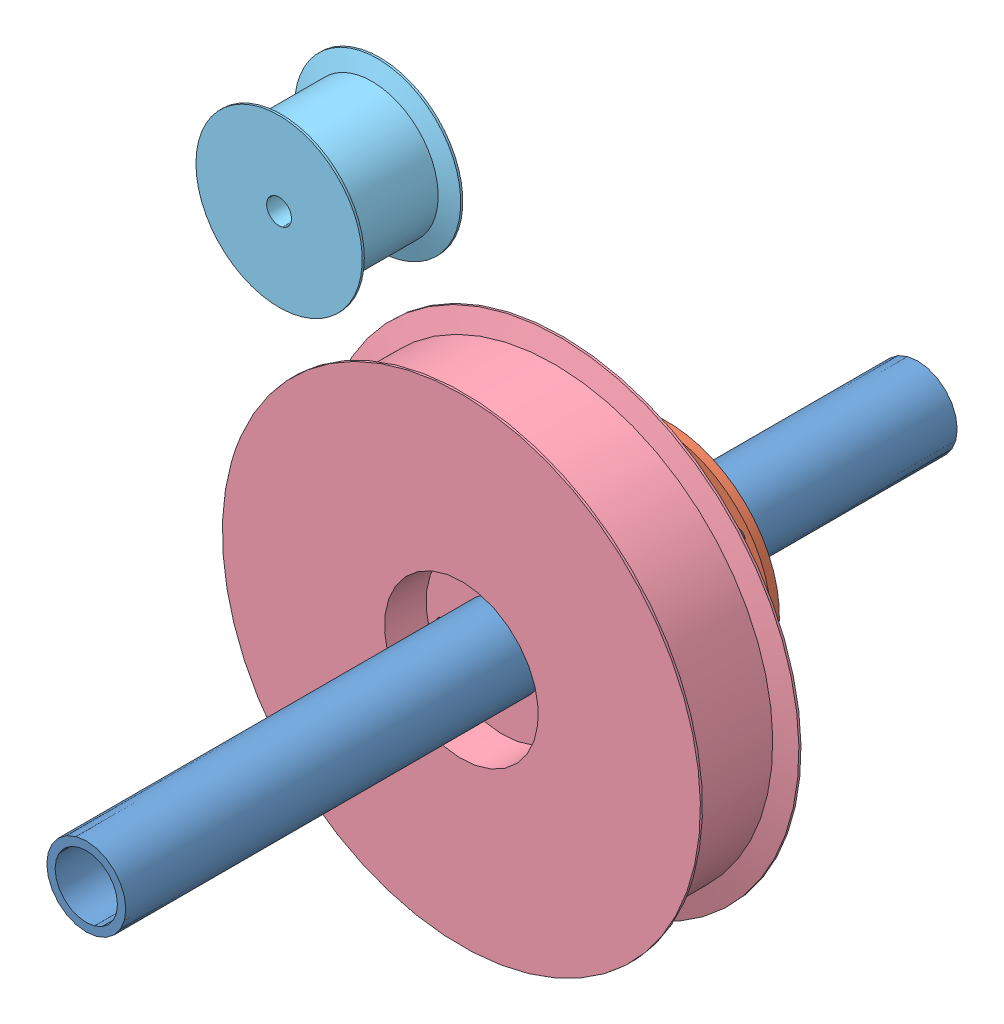
SolidWorks assembly Combine, configuration 預設. Lengths in mm.
Overall size (146.58 166.88 200).
5 component instances, 5 part files, 6 mates.
Components (placement in the parent):
- Shaft-1: Shaft [預設] at (-5.4875 -0.4573 200) size (19 19 200)
- Brake-1: Brake [預設] at (-5.4875 -0.4573 260.2705) x (0.812084 0.58354 0) z (0 0 1) size (54 54 22.3)
- Flange-1: Flange [預設] at (-5.4875 -0.4573 285.5705) x (0.923728 0.383049 0) z (0 0 -1) size (43 43 4.4)
- RollerBig-1: RollerBig [預設] at (-5.4875 -0.4573 285.5705) x (-0.943655 0.330932 0) z (0 0 1) size (115 115 24.2)
- RollerSmall20-1: RollerSmall20 [預設] at (-49.3412 73.1381 285.5705) size (40 40 24.2)
Mates (geometry in assembly coordinates):
- 同軸心1: concentric: circle of Brake-1; circle of Flange-1
- 重合/共線/共點1: coincident: plane of Brake-1 through (-5.4875 -0.4573 282.5705) normal (0 0 1); plane of Flange-1 through (-5.4875 -0.4573 282.5705) normal (0 0 -1)
- 同軸心2: concentric: circle of Brake-1; circle of RollerBig-1
- 重合/共線/共點3: coincident: plane of Flange-1 through (-5.4875 -0.4573 285.5705) normal (0 0 1); plane of RollerBig-1 through (-5.4875 -0.4573 285.5705) normal (0 0 -1)
- 同軸心4: concentric: cylinder of Shaft-1 through (-5.4875 -0.4573 400) axis (0 0 -1) radius 9.5; cylinder of Brake-1 through (-5.4875 -0.4573 282.5705) axis (0 0 -1) radius 9.5
- 重合/共線/共點4: coincident: plane of RollerBig-1 through (-5.4875 -0.4573 285.5705) normal (0 0 -1); plane of RollerSmall20-1 through (-49.3412 73.1381 285.5705) normal (0 0 -1)
